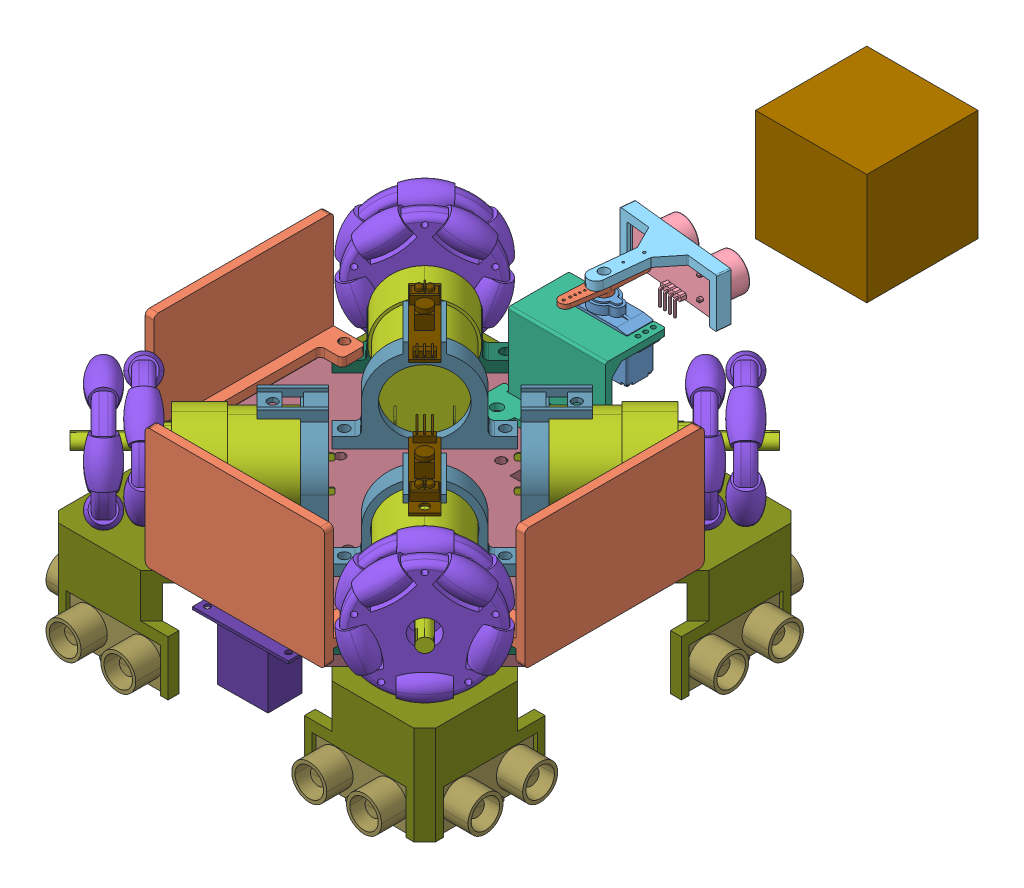
SolidWorks assembly ultrasonicservomount, configuration Default. Lengths in mm.
Overall size (205.04 116.14 334.06).
50 component instances, 20 part files, 17 mates.
Components (placement in the parent):
- SM-S2309S-1: SM-S2309S [Default] at (-11.6058 -12.8949 -67.6863) size (37 29.3 12.25)
- SM-S2309S-Arm-1: SM-S2309S-Arm [Default] at (-11.6058 0.3551 -67.6863) x (0.104626 0 -0.994512) z (0.994512 0 0.104626) size (37.6 4 7.2)
- SM-S2309S-Screw-1: SM-S2309S-Screw [Default] at (-11.6058 1.5551 -67.6863) x (0.104626 0 -0.994512) z (0.994512 0 0.104626) size (3.8 6.73 3.8)
- Sensor Ultrasónico-1: Sensor Ultrasónico [Predeterminado] at (-8.2839 -5.8149 -99.2621) x (-0.994512 0 -0.104626) z (0.104626 0 -0.994512) size (45.42 26.14 17.7)
- SensorServoMount-1: SensorServoMount [Default] at (-30.7647 6.3551 -102.6326) x (0.994512 0 0.104626) z (0.104626 0 -0.994512) size (49.42 22.34 39.56)
- ServoRobotMount-1: ServoRobotMount [Default] at (16.6315 -45.0449 12.2989) x (0 0 1) z (1 0 0) size (44.11 37 54.34)
- 444 - Robot Assembly revF.STEP-1: 444 - Robot Assembly revF.STEP [Default] at (-11.5658 9.3551 14.2492) x (0 0 -1) z (-1 0 0) size (334.06 116.14 205.04)
  - 444 - 12V Motor.STEP-1: 444 - 12V Motor.STEP [Default] at (-24.8359 36 -24.8359) x (0.707107 0 -0.707107) z (0 1 0) size (36.8 85.65 36.8)
  - 444 - 12V Motor.STEP-2: 444 - 12V Motor.STEP [Default] at (-24.8359 36 24.8359) x (-0.707107 0 -0.707107) z (0 1 0) size (36.8 85.65 36.8)
  - 444 - 12V Motor.STEP-3: 444 - 12V Motor.STEP [Default] at (24.8359 36 24.8359) x (-0.707107 0 0.707107) z (0 1 0) size (36.8 85.65 36.8)
  - 444 - 12V Motor.STEP-4: 444 - 12V Motor.STEP [Default] at (24.8359 36 -24.8359) x (0.707107 0 0.707107) z (0 1 0) size (36.8 85.65 36.8)
  - 444 - Omni Wheel Half.STEP-1: 444 - Omni Wheel Half.STEP [Default] at (-64.1652 29 64.1652) x (0.707107 -0.000232 0.707107) z (-0.707107 0 0.707107) size (58 56.67 13)
  - 444 - Omni Wheel Half.STEP-2: 444 - Omni Wheel Half.STEP [Default] at (-73.3576 29 73.3576) x (0.574296 -0.583411 0.574296) z (-0.707107 0 0.707107) size (58 56.67 13)
  - 444 - Omni Wheel Half.STEP-3: 444 - Omni Wheel Half.STEP [Default] at (-73.3576 29 -73.3576) x (0.707107 -0.000249 -0.707107) z (0.707107 0 0.707107) size (58 56.67 13)
  - 444 - Omni Wheel Half.STEP-4: 444 - Omni Wheel Half.STEP [Default] at (-64.1652 29 -64.1652) x (0.575656 -0.580723 -0.575656) z (0.707107 0 0.707107) size (58 56.67 13)
  - 444 - Omni Wheel Half.STEP-5: 444 - Omni Wheel Half.STEP [Default] at (73.3576 29 73.3576) x (0.579556 -0.572912 -0.579556) z (0.707107 0 0.707107) size (58 56.67 13)
  - 444 - Omni Wheel Half.STEP-6: 444 - Omni Wheel Half.STEP [Default] at (64.1652 29 64.1652) x (0.707107 0 -0.707107) z (0.707107 0 0.707107) size (58 56.67 13)
  - 444 - Omni Wheel Half.STEP-7: 444 - Omni Wheel Half.STEP [Default] at (73.3576 29 -73.3576) x (0.707107 0 0.707107) z (-0.707107 0 0.707107) size (58 56.67 13)
  - 444 - Omni Wheel Half.STEP-8: 444 - Omni Wheel Half.STEP [Default] at (64.1652 29 -64.1652) x (0.576027 -0.579988 0.576027) z (-0.707107 0 0.707107) size (58 56.67 13)
  - 444 - Load Block.STEP-1: 444 - Load Block.STEP [Default] at (202.6405 0 0.6646) size (50.8 50.8 50.8)
  - 444 - Arduino Uno.STEP-1: 444 - Arduino Uno.STEP [Default] at (27 92.8125 31.08) size (53.35 21.02 76.06)
  - 444 - 12V NiMH Battery.STEP-1: 444 - 12V NiMH Battery.STEP [Default] at (22.77 59.1625 -36) x (0 0 1) z (-1 0 0) size (66.67 26.67 48.77)
  - 444 - HC-SR04 Ultrasonic.STEP-1: 444 - HC-SR04 Ultrasonic.STEP [Default] at (-56.1358 94.1625 84.3858) size (45 26.15 17.25)
  - 444 - HC-SR04 Ultrasonic.STEP-2: 444 - HC-SR04 Ultrasonic.STEP [Default] at (-84.3858 94.1625 -56.1358) x (0 0 1) z (-1 0 0) size (45 26.15 17.25)
  - 444 - HC-SR04 Ultrasonic.STEP-3: 444 - HC-SR04 Ultrasonic.STEP [Default] at (-56.1358 94.1625 -84.3858) x (-1 0 0) z (0 0 -1) size (45 26.15 17.25)
  - 444 - HC-SR04 Ultrasonic.STEP-4: 444 - HC-SR04 Ultrasonic.STEP [Default] at (-84.3858 94.1625 56.1358) x (0 0 1) z (-1 0 0) size (45 26.15 17.25)
  - 444-Acrylic-Baseplate-2.STEP-1: 444-Acrylic-Baseplate-2.STEP [Default] at (0 59.1625 0) x (1 0 0) z (0 -1 0) size (165.1 165.1 4.76)
  - 444 - Motor Mount Rear.STEP-1: 444 - Motor Mount Rear.STEP [Default] at (24.8359 54.4 24.8359) x (-0.707107 0 0.707107) z (0 1 0) size (60 23 42.4)
  - 444 - Motor Mount Front.STEP-1: 444 - Motor Mount Front.STEP [Default] at (57.8013 54.4 57.8013) x (-0.707107 0 0.707107) z (0.707107 0 0.707107) size (60 21.5 10)
  - 444 - Motor Mount Rear.STEP-2: 444 - Motor Mount Rear.STEP [Default] at (-24.8359 54.4 24.8359) x (-0.707107 0 -0.707107) z (0 1 0) size (60 23 42.4)
  - 444 - Motor Mount Front.STEP-2: 444 - Motor Mount Front.STEP [Default] at (-57.8013 54.4 57.8013) x (-0.707107 0 -0.707107) z (-0.707107 0 0.707107) size (60 21.5 10)
  - 444 - Motor Mount Rear.STEP-3: 444 - Motor Mount Rear.STEP [Default] at (-24.8359 54.4 -24.8359) x (0.707107 0 -0.707107) z (0 1 0) size (60 23 42.4)
  - 444 - Motor Mount Front.STEP-3: 444 - Motor Mount Front.STEP [Default] at (-57.8013 54.4 -57.8013) x (0.707107 0 -0.707107) z (-0.707107 0 -0.707107) size (60 21.5 10)
  - 444 - Motor Mount Front.STEP-4: 444 - Motor Mount Front.STEP [Default] at (57.8013 54.4 -57.8013) x (0.707107 0 0.707107) z (0.707107 0 -0.707107) size (60 21.5 10)
  - 444 - Motor Mount Rear.STEP-4: 444 - Motor Mount Rear.STEP [Default] at (24.8359 54.4 -24.8359) x (0.707107 0 0.707107) z (0 1 0) size (60 23 42.4)
  - 444 - Ultrasonic Sensor Holder.STEP-1: 444 - Ultrasonic Sensor Holder.STEP [Default] at (-86.1358 59.1625 86.1358) size (55 45 55)
  - 444 - Ultrasonic Sensor Holder.STEP-2: 444 - Ultrasonic Sensor Holder.STEP [Default] at (-86.1358 59.1625 -86.1358) x (0 0 1) z (-1 0 0) size (55 45 55)
  - 444 - Ultrasonic Sensor Holder.STEP-3: 444 - Ultrasonic Sensor Holder.STEP [Default] at (86.1358 59.1625 -86.1358) x (-1 0 0) z (0 0 -1) size (55 45 55)
  - 444 - Ultrasonic Sensor Holder.STEP-4: 444 - Ultrasonic Sensor Holder.STEP [Default] at (86.1358 59.1625 86.1358) x (0 0 -1) z (1 0 0) size (55 45 55)
  - 444 - HC-SR04 Ultrasonic.STEP-5: 444 - HC-SR04 Ultrasonic.STEP [Default] at (56.1358 94.1625 -84.3858) x (-1 0 0) z (0 0 -1) size (45 26.15 17.25)
  - 444 - HC-SR04 Ultrasonic.STEP-6: 444 - HC-SR04 Ultrasonic.STEP [Default] at (84.3858 94.1625 -56.1358) x (0 0 -1) z (1 0 0) size (45 26.15 17.25)
  - 444 - HC-SR04 Ultrasonic.STEP-7: 444 - HC-SR04 Ultrasonic.STEP [Default] at (84.3858 94.1625 56.1358) x (0 0 -1) z (1 0 0) size (45 26.15 17.25)
  - 444 - HC-SR04 Ultrasonic.STEP-8: 444 - HC-SR04 Ultrasonic.STEP [Default] at (56.1358 94.1625 84.3858) size (45 26.15 17.25)
  - 444 - L298N Controller.STEP-1: 444 - L298N Controller.STEP [Default] at (-38.7442 65.2958 24.0053) x (0.008727 0 -0.999962) z (0.999962 0 0.008727) size (43.4 26.21 43.75)
  - 444 - IR Sensor.STEP-1: 444 - IR Sensor.STEP [Default] at (-41.658 13.5 -49.0402) x (0.707107 0 0.707107) z (0.707107 0 -0.707107) size (47.63 9.5 10.44)
  - 444 - Battery Holder v2.STEP-1: 444 - Battery Holder v2.STEP [Default] at (0 59.1625 0) size (78 35 83.15)
  - 444 - IR Sensor.STEP-2: 444 - IR Sensor.STEP [Default] at (41.658 13.5 49.0402) x (-0.707107 0 -0.707107) z (-0.707107 0 0.707107) size (47.63 9.5 10.44)
  - 444 - Blinders.STEP-1: 444 - Blinders.STEP [Default] at (-41 49.4 -86.7147) size (82 55.35 19)
  - 444 - Blinders.STEP-2: 444 - Blinders.STEP [Default] at (-86.7147 49.4 41) x (0 0 -1) z (1 0 0) size (82 55.35 19)
  - 444 - Blinders.STEP-3: 444 - Blinders.STEP [Default] at (41 49.4 86.7147) x (-1 0 0) z (0 0 -1) size (82 55.35 19)
Mates (geometry in assembly coordinates):
- Coincident1: coincident: line of SM-S2309S-1 through (-11.6058 42.1051 -67.6863) axis (0 -1 0); line of SM-S2309S-Arm-1 through (-11.6058 55.3551 -67.6863) axis (0 -1 0)
- Coincident2: coincident: plane of SM-S2309S-1 through (-10.6058 0.8051 -67.6863) normal (0 1 0); plane of SM-S2309S-Arm-1 through (-11.4881 0.8051 -68.8051) normal (0 -1 0)
- Coincident3: coincident: line of SM-S2309S-Arm-1 through (-11.6058 55.3551 -67.6863) axis (0 -1 0); line of SM-S2309S-Screw-1 through (-11.6058 56.5551 -67.6863) axis (0 -1 0)
- Coincident4: coincident: plane of SM-S2309S-Arm-1 through (-11.3704 1.5551 -69.924) normal (0 1 0); plane of SM-S2309S-Screw-1 through (-11.4829 1.5551 -68.8549) normal (0 -1 0)
- Coincident5: coincident: plane of SM-S2309S-Arm-1 through (-11.6058 0.3551 -67.6863) normal (0.994512 0 0.104626); plane of SM-S2309S-Screw-1 through (-11.6058 1.5551 -67.6863) normal (0.994512 0 0.104626)
- Concentric2: concentric: cylinder of SM-S2309S-Arm-1 through (-10.7688 40.6383 -75.6424) axis (0 -1 0) radius 0.45; cylinder of SensorServoMount-1 through (-10.7688 2.3551 -75.6424) axis (0 1 0) radius 0.45
- Coincident10: coincident: plane of Sensor Ultrasónico-1 through (14.134 4.3551 -95.2948) normal (0 1 0); plane of SensorServoMount-1 through (-30.7647 4.3551 -102.6326) normal (0 -1 0)
- Coincident12: coincident: plane of Sensor Ultrasónico-1 through (14.134 -15.9849 -95.2948) normal (0.994512 0 0.104626); plane of SensorServoMount-1 through (13.9352 51.9098 -93.4052) normal (-0.994512 0 -0.104626)
- Coincident13: coincident: plane of Sensor Ultrasónico-1 through (-8.2839 -5.8149 -99.2621) normal (0.104626 0 -0.994512); plane of SensorServoMount-1 through (-30.8693 51.9098 -101.6381) normal (-0.104626 0 0.994512)
- Concentric3: concentric: cylinder of SM-S2309S-Arm-1 through (-11.6058 55.3551 -67.6863) axis (0 1 0) radius 2.25; cylinder of SensorServoMount-1 through (-11.6058 2.3551 -67.6863) axis (0 1 0) radius 2.25
- Coincident15: coincident: plane of SM-S2309S-1 through (5.0142 -11.0449 -61.5613) normal (0 1 0); plane of ServoRobotMount-1 through (16.6315 -11.0449 12.2989) normal (0 -1 0)
- Parallel3: parallel: plane of SM-S2309S-1 through (9.2642 -11.0449 -61.5613) normal (1 0 0); plane of ServoRobotMount-1 through (10.6042 -8.0449 -49.2508) normal (1 0 0)
- Coincident16: coincident: plane of ServoRobotMount-1 through (-30.6158 -45.0449 -37.8208) normal (0 -1 0); plane of 444 - Robot Assembly revF.STEP-1/444-Acrylic-Baseplate-2.STEP-1 through (-11.5658 -45.0449 14.2492) normal (0 1 0)
- Concentric5: concentric: cylinder of ServoRobotMount-1 through (-30.6158 -42.0449 -37.8208) axis (0 -1 0) radius 2.5; cylinder of 444 - Robot Assembly revF.STEP-1/444-Acrylic-Baseplate-2.STEP-1 through (-30.6158 -45.0439 -37.8208) axis (0 -1 0) radius 2.1463
- Concentric6: concentric: cylinder of ServoRobotMount-1 through (7.4842 -42.0449 -37.8208) axis (0 -1 0) radius 2.5; cylinder of 444 - Robot Assembly revF.STEP-1/444-Acrylic-Baseplate-2.STEP-1 through (7.4842 -45.0439 -37.8208) axis (0 -1 0) radius 2.1463
- Coincident17: coincident: plane of SM-S2309S-Arm-1 through (-11.2292 2.3551 -71.2666) normal (0 1 0); plane of SensorServoMount-1 through (-11.9458 2.3551 -64.4542) normal (0 -1 0)
- Concentric7: concentric: cylinder of SM-S2309S-1 through (-21.1108 -2.3949 -67.6863) axis (0 -1 0) radius 1; cylinder of ServoRobotMount-1 through (-21.1108 -11.0449 -67.6863) axis (0 1 0) radius 1
